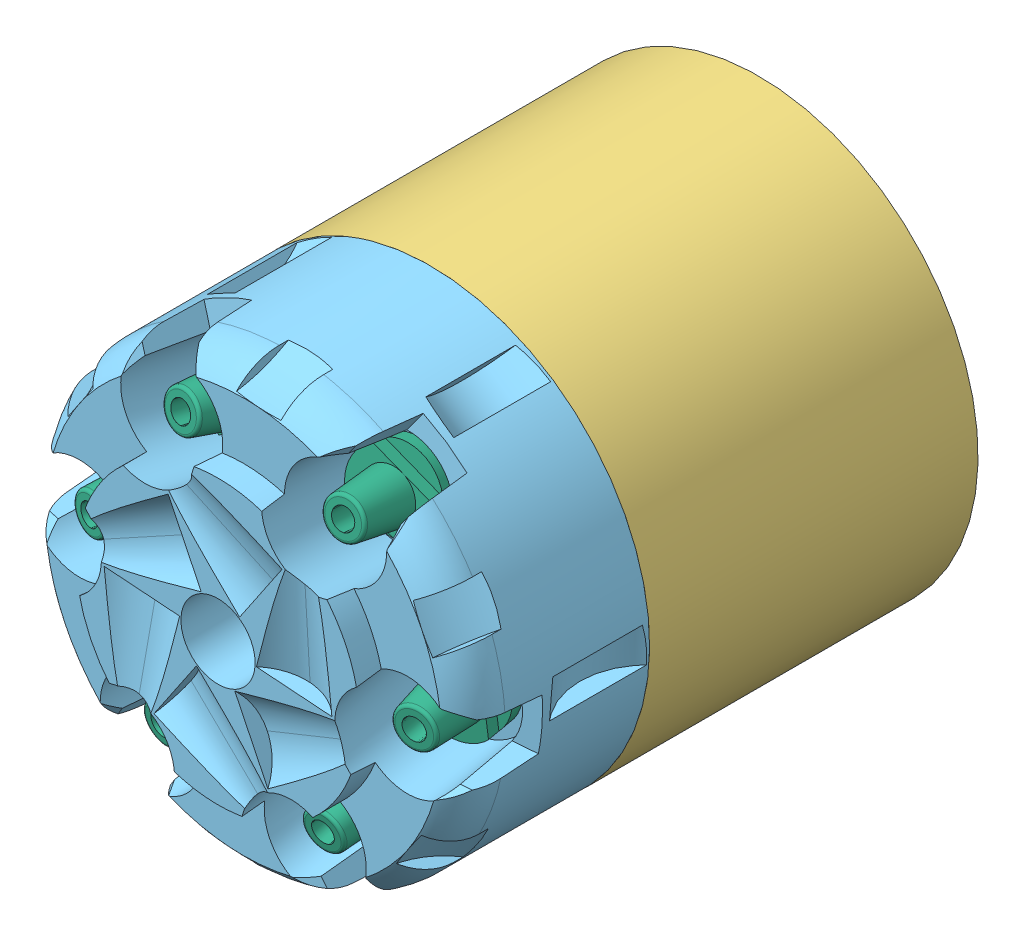
SolidWorks assembly Cylinder_cut_inner_piston.44, configuration Default. Lengths in mm.
Overall size (55.41 55.04 52.16).
22 component instances, 7 part files, 22 mates.
Components (placement in the parent):
- 5mm-1: 5mm [Default] at (0.2237 0.2935 0.3421)
- Inner_cylinder.44-8: Inner_cylinder.44 [Default] at (14.3811 3.1391 19.6157) x (0.594907 -0.803795 0) z (0 0 1) size (11.4 11.4 19.82)
- Piston.44-7: Piston.44 [Default] at (14.3811 3.1391 50.6623) x (0.802966 0.596025 0) z (0 0 -1) size (9.4 9.4 17)
- Inner_cylinder.44-9: Inner_cylinder.44 [Default] at (8.8349 14.5641 19.6157) x (0.99356 0.113307 0) z (0 0 1) size (11.4 11.4 19.82)
- Inner_cylinder.44-10: Inner_cylinder.44 [Default] at (-3.8325 15.4735 19.6157) x (0.398653 0.917102 0) z (0 0 1) size (11.4 11.4 19.82)
- Inner_cylinder.44-11: Inner_cylinder.44 [Default] at (-10.9537 4.9579 19.6157) x (-0.594907 0.803795 0) z (0 0 1) size (11.4 11.4 19.82)
- Inner_cylinder.44-12: Inner_cylinder.44 [Default] at (-5.4076 -6.4671 19.6157) x (-0.99356 -0.113307 0) z (0 0 1) size (11.4 11.4 19.82)
- Inner_cylinder.44-13: Inner_cylinder.44 [Default] at (7.2598 -7.3765 19.6157) x (-0.398653 -0.917102 0) z (0 0 1) size (11.4 11.4 19.82)
- Piston.44-8: Piston.44 [Default] at (8.8349 14.5641 50.6623) x (-0.11469 0.993401 0) z (0 0 -1) size (9.4 9.4 17)
- Piston.44-9: Piston.44 [Default] at (-3.8325 15.4735 50.6623) x (-0.917656 0.397377 0) z (0 0 -1) size (9.4 9.4 17)
- Piston.44-10: Piston.44 [Default] at (-10.9537 4.9579 50.6623) x (-0.802966 -0.596025 0) z (0 0 -1) size (9.4 9.4 17)
- Piston.44-11: Piston.44 [Default] at (-5.4076 -6.4671 50.6623) x (0.11469 -0.993401 0) z (0 0 -1) size (9.4 9.4 17)
- Piston.44-12: Piston.44 [Default] at (7.2598 -7.3765 50.6623) x (0.917656 -0.397377 0) z (0 0 -1) size (9.4 9.4 17)
- Cylinder_cut.44-3: Cylinder_cut.44 [Default] at (1.8525 14.1014 36.1993) x (0.980123 -0.19839 0) z (0 0 1) size (43.32 43.9 52.16)
- Peg-1: Peg [Default] at (2.9868 21.7828 45.5933) size (2.54 2.54 10.16)
- Back_part_of_cylinder-2: Back_part_of_cylinder [Default] at (10.4892 8.9547 36.1993) x (0.318251 -0.948007 0) z (0 0 1) size (43.32 43.9 21.29)
- Nippel-7: Nippel [Default] at (-316.711 193.3723 129.2789) x (0.504601 -0.432091 -0.747446) z (-0.572099 -0.815733 0.085342) size (12.39 9.96 7.5)
- Nippel-8: Nippel [Default] at (-321.4579 -177.0535 129.2789) x (0.626502 0.220952 -0.747446) z (0.420396 -0.903318 0.085342) size (12.39 9.96 7.5)
- Nippel-9: Nippel [Default] at (-3.0332 -366.3773 129.2789) x (0.121901 0.653042 -0.747446) z (0.992495 -0.087586 0.085342) size (12.39 9.96 7.5)
- Nippel-10: Nippel [Default] at (320.1383 -185.2753 129.2789) x (-0.504601 0.432091 -0.747446) z (0.572099 0.815733 0.085342) size (12.39 9.96 7.5)
- Nippel-11: Nippel [Default] at (324.8852 185.1505 129.2789) x (-0.626502 -0.220952 -0.747446) z (-0.420396 0.903318 0.085342) size (12.39 9.96 7.5)
- Nippel-12: Nippel [Default] at (6.4605 374.4742 129.2789) x (-0.121901 -0.653042 -0.747446) z (-0.992495 0.087586 0.085342) size (12.39 9.96 7.5)
Mates (geometry in assembly coordinates):
- Concentric6: concentric: cylinder of Inner_cylinder.44-8 through (14.3811 3.1391 17.3137) axis (0 0 1) radius 4.7; cylinder of Piston.44-7 through (14.3811 3.1391 33.6623) axis (0 0 1) radius 4.09
- Lock1: lock: unknown of Inner_cylinder.44-9; unknown of Cylinder_cut.44-3
- Lock2: lock: unknown of Inner_cylinder.44-10; unknown of Cylinder_cut.44-3
- Lock3: lock: unknown of Inner_cylinder.44-8; unknown of Cylinder_cut.44-3
- Lock4: lock: unknown of Inner_cylinder.44-13; unknown of Cylinder_cut.44-3
- Lock5: lock: unknown of Inner_cylinder.44-12; unknown of Cylinder_cut.44-3
- Lock6: lock: unknown of Inner_cylinder.44-11; unknown of Cylinder_cut.44-3
- Lock7: lock: unknown of Inner_cylinder.44-9; unknown of Cylinder_cut.44-3
- Lock8: lock: unknown of Piston.44-8; unknown of Cylinder_cut.44-3
- Lock9: lock: unknown of Piston.44-9; unknown of Cylinder_cut.44-3
- Lock10: lock: unknown of Piston.44-10; unknown of Cylinder_cut.44-3
- Lock11: lock: unknown of Piston.44-11; unknown of Cylinder_cut.44-3
- Lock12: lock: unknown of Piston.44-12; unknown of Cylinder_cut.44-3
- Lock13: lock: unknown of Piston.44-7; unknown of Cylinder_cut.44-3
- Lock14: lock: unknown of Cylinder_cut.44-3
- Concentric7: concentric: cylinder of Cylinder_cut.44-3 through (2.9868 21.7828 45.5933) axis (0 0 1) radius 1.27; cylinder of Peg-1 through (2.9868 21.7828 55.7533) axis (0 0 -1) radius 1.27
- Distance1: distance = 5.08 mm: plane of Peg-1 through (2.9868 21.7828 55.7533) normal (0 0 1); plane of Cylinder_cut.44-3 through (-20.0964 31.1764 50.6733) normal (0 0 1)
- Concentric8: concentric: cylinder of Peg-1 through (2.9868 21.7828 55.7533) axis (0 0 -1) radius 1.27; cylinder of Back_part_of_cylinder-2 through (2.9868 21.7828 55.7533) axis (0 0 -1) radius 1.27
- Concentric9: concentric: circle of Cylinder_cut.44-3; circle of Back_part_of_cylinder-2
- Coincident1: coincident: plane of Cylinder_cut.44-3 through (-20.0964 31.1764 50.6733) normal (0 0 1); plane of Back_part_of_cylinder-2 through (14.3021 36.5005 50.6733) normal (0 0 -1)
- Concentric10: concentric: cylinder of Back_part_of_cylinder-2 through (-5.0476 17.9768 68.1899) axis (0.075833 -0.156215 -0.984808) radius 2.067; cylinder of Nippel-7 through (-4.532 16.9145 61.4932) axis (-0.075833 0.156215 0.984808) radius 2.5
- Coincident2: coincident: plane of Back_part_of_cylinder-2 through (-6.308 15.84 60.4099) normal (-0.075833 0.156215 0.984808); plane of Nippel-7 through (-2.8116 15.4688 60.738) normal (0.075833 -0.156215 -0.984808)
